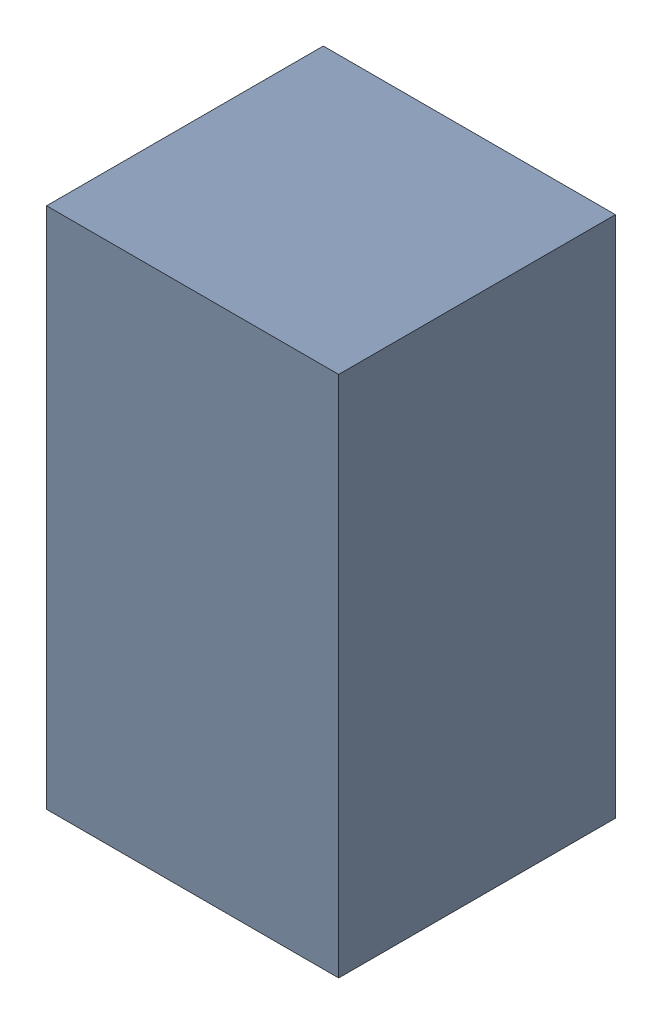
SolidWorks assembly R2_1, configuration Default. Lengths in mm.
Overall size (0.95 1.7 0.9).
2 component instances, 1 part files, 0 mates.
Components (placement in the parent):
- 5808185088-1: 5808185088 [Default] at (16.129 9.767 0) size (0.95 1.7 0.9)
  - Extruded_1_2-1: Extruded_1_2 [Default] at origin size (0.95 1.7 0.9)
